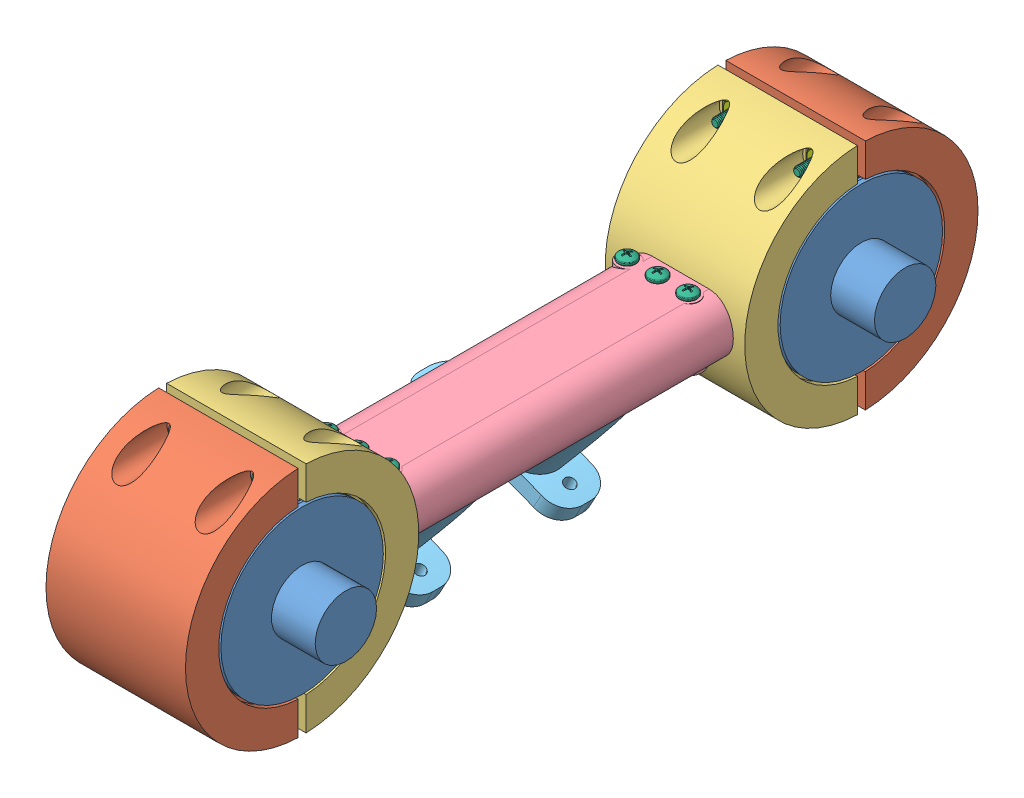
SolidWorks assembly spoilerassm, configuration Default. Lengths in mm.
Overall size (129.47 120.96 369.32).
48 component instances, 8 part files, 38 mates.
Components (placement in the parent):
- Copy of edf^spoilerassm-1: Copy of edf^spoilerassm [Default] at (232.7544 176.9652 -40.9789) size (85.4 108.65 122.15) (virtual)
  - Copy of edf^Copy of edf_spoilerassm-1: Copy of edf^Copy of edf_spoilerassm [Default] at (17.7715 0 -26.4391) size (85.4 90.8 94.1) (virtual)
  - Part2^Copy of edf_spoilerassm-1: Part2^Copy of edf_spoilerassm [Default] at origin size (65 108.65 52.51) (virtual)
  - Copy of Part2^Copy of edf_spoilerassm-2: Copy of Part2^Copy of edf_spoilerassm [Default] at (-3.166 0 -52.8782) x (1 0 0) z (0 0 -1) size (65 108.65 65.94) (virtual)
- Part3^spoilerassm-1: Part3^spoilerassm [Default] at (229.5884 176.9652 -0.616) x (-1 0 0) z (0 0 1) size (52.1 38.79 156.47) (virtual)
- Copy of edf^spoilerassm-2: Copy of edf^spoilerassm [Default] at (232.7544 176.9652 166.7469) x (1 0 0) z (0 0 -1) size (85.4 108.65 122.15) (virtual)
  - Copy of edf^Copy of edf_spoilerassm-1: Copy of edf^Copy of edf_spoilerassm [Default] at (17.7715 0 -26.4391) size (85.4 90.8 94.1) (virtual)
  - Part2^Copy of edf_spoilerassm-1: Part2^Copy of edf_spoilerassm [Default] at origin size (65 108.65 52.51) (virtual)
  - Copy of Part2^Copy of edf_spoilerassm-2: Copy of Part2^Copy of edf_spoilerassm [Default] at (-3.166 0 -52.8782) x (1 0 0) z (0 0 -1) size (65 108.65 65.94) (virtual)
- scooterbase-1: scooterbase [Default] at (218.1937 -0.4538 -1.886) size (199.84 127 129.54) (hidden)
- Part1^spoilerassm-1: Part1^spoilerassm [Default] at (218.1937 -0.4538 127.654) size (101.69 64.87 27.24) (virtual)
- Part1^spoilerassm-2: Part1^spoilerassm [Default] at (218.1937 -0.4538 57.804) size (101.69 64.87 27.24) (virtual)
- 91735A199_316 Stainless Steel Pan Head Phillips Screw-1: 91735A199_316 Stainless Steel Pan Head Phillips Screw [91735A199] at (265.7603 223.5385 -74.346) x (-0.458456 -0.888717 0) z (0 0 -1) size (8.18 8.18 28.44)
- 91735A199_316 Stainless Steel Pan Head Phillips Screw-2: 91735A199_316 Stainless Steel Pan Head Phillips Screw [91735A199] at (304.63 223.5385 -73.6731) x (-0.458456 -0.888717 0) z (0 0 -1) size (8.18 8.18 28.44)
- 91735A199_316 Stainless Steel Pan Head Phillips Screw-3: 91735A199_316 Stainless Steel Pan Head Phillips Screw [91735A199] at (304.63 223.5385 200.114) x (0.763911 -0.645321 0) z (0 0 1) size (8.18 8.18 28.44)
- 91735A199_316 Stainless Steel Pan Head Phillips Screw-4: 91735A199_316 Stainless Steel Pan Head Phillips Screw [91735A199] at (265.7603 223.5385 200.114) x (-0.385326 -0.922781 0) z (0 0 1) size (8.18 8.18 28.44)
- 90480A009_Low-Strength Steel Hex Nut-2: 90480A009_Low-Strength Steel Hex Nut [90480A009] at (304.63 223.5385 184.6705) x (0.999997 0.002605 0) z (-0.002605 0.999997 0) size (8.73 3.79 10.08)
- 90480A009_Low-Strength Steel Hex Nut-3: 90480A009_Low-Strength Steel Hex Nut [90480A009] at (265.7603 223.5385 184.6705) x (0.52328 0.852161 0) z (-0.852161 0.52328 0) size (8.73 3.79 10.08)
- 90480A009_Low-Strength Steel Hex Nut-4: 90480A009_Low-Strength Steel Hex Nut [90480A009] at (265.7603 223.5385 -58.9025) x (0.999763 0.021771 0) z (-0.021771 0.999763 0) size (8.73 3.79 10.08)
- 90480A009_Low-Strength Steel Hex Nut-5: 90480A009_Low-Strength Steel Hex Nut [90480A009] at (304.63 223.5385 -58.9025) x (0.502449 0.864607 0) z (-0.864607 0.502449 0) size (8.73 3.79 10.08)
- 91735A199_316 Stainless Steel Pan Head Phillips Screw-5: 91735A199_316 Stainless Steel Pan Head Phillips Screw [91735A199] at (304.63 130.3205 -73.6731) x (-0.458456 -0.888717 0) z (0 0 -1) size (8.18 8.18 28.44)
- 91735A199_316 Stainless Steel Pan Head Phillips Screw-6: 91735A199_316 Stainless Steel Pan Head Phillips Screw [91735A199] at (304.63 130.3205 200.114) x (0.763911 -0.645321 0) z (0 0 1) size (8.18 8.18 28.44)
- 91735A199_316 Stainless Steel Pan Head Phillips Screw-7: 91735A199_316 Stainless Steel Pan Head Phillips Screw [91735A199] at (265.7603 130.3205 200.114) x (-0.385326 -0.922781 0) z (0 0 1) size (8.18 8.18 28.44)
- 90480A009_Low-Strength Steel Hex Nut-6: 90480A009_Low-Strength Steel Hex Nut [90480A009] at (304.63 130.3205 184.6705) x (0.999997 0.002605 0) z (-0.002605 0.999997 0) size (8.73 3.79 10.08)
- 90480A009_Low-Strength Steel Hex Nut-7: 90480A009_Low-Strength Steel Hex Nut [90480A009] at (265.7603 130.3205 184.6705) x (0.52328 0.852161 0) z (-0.852161 0.52328 0) size (8.73 3.79 10.08)
- 90480A009_Low-Strength Steel Hex Nut-8: 90480A009_Low-Strength Steel Hex Nut [90480A009] at (265.7603 130.3205 -58.9025) x (0.999763 0.021771 0) z (-0.021771 0.999763 0) size (8.73 3.79 10.08)
- 90480A009_Low-Strength Steel Hex Nut-9: 90480A009_Low-Strength Steel Hex Nut [90480A009] at (304.63 130.3205 -58.9025) x (0.502449 0.864607 0) z (-0.864607 0.502449 0) size (8.73 3.79 10.08)
- 91735A199_316 Stainless Steel Pan Head Phillips Screw-8: 91735A199_316 Stainless Steel Pan Head Phillips Screw [91735A199] at (265.7603 130.3205 -74.346) x (-0.458456 -0.888717 0) z (0 0 -1) size (8.18 8.18 28.44)
- 90480A009_Low-Strength Steel Hex Nut-10: 90480A009_Low-Strength Steel Hex Nut [90480A009] at (294.8896 162.5507 -7.3301) x (-0.010668 0 0.999943) z (-0.999943 0 -0.010668) size (8.73 3.79 10.08)
- 91735A199_316 Stainless Steel Pan Head Phillips Screw-9: 91735A199_316 Stainless Steel Pan Head Phillips Screw [91735A199] at (294.8896 189.7922 -7.3301) x (-0.174317 0 0.98469) z (0 1 0) size (8.18 8.18 28.44)
- 90480A009_Low-Strength Steel Hex Nut-11: 90480A009_Low-Strength Steel Hex Nut [90480A009] at (294.8896 162.5507 132.8779) x (-0.010668 0 0.999943) z (-0.999943 0 -0.010668) size (8.73 3.79 10.08)
- 90480A009_Low-Strength Steel Hex Nut-12: 90480A009_Low-Strength Steel Hex Nut [90480A009] at (280.6656 162.5507 -7.3301) x (-0.010668 0 0.999943) z (-0.999943 0 -0.010668) size (8.73 3.79 10.08)
- 90480A009_Low-Strength Steel Hex Nut-13: 90480A009_Low-Strength Steel Hex Nut [90480A009] at (280.6656 162.5507 132.8779) x (-0.010668 0 0.999943) z (-0.999943 0 -0.010668) size (8.73 3.79 10.08)
- 90480A009_Low-Strength Steel Hex Nut-14: 90480A009_Low-Strength Steel Hex Nut [90480A009] at (266.4416 162.5507 -7.3301) x (-0.010668 0 0.999943) z (-0.999943 0 -0.010668) size (8.73 3.79 10.08)
- 90480A009_Low-Strength Steel Hex Nut-15: 90480A009_Low-Strength Steel Hex Nut [90480A009] at (266.4416 162.5507 132.8779) x (-0.010668 0 0.999943) z (-0.999943 0 -0.010668) size (8.73 3.79 10.08)
- 91735A199_316 Stainless Steel Pan Head Phillips Screw-10: 91735A199_316 Stainless Steel Pan Head Phillips Screw [91735A199] at (294.8896 189.7922 132.8779) x (-0.174317 0 0.98469) z (0 1 0) size (8.18 8.18 28.44)
- 91735A199_316 Stainless Steel Pan Head Phillips Screw-11: 91735A199_316 Stainless Steel Pan Head Phillips Screw [91735A199] at (280.6656 189.7922 -7.3301) x (-0.174317 0 0.98469) z (0 1 0) size (8.18 8.18 28.44)
- 91735A199_316 Stainless Steel Pan Head Phillips Screw-12: 91735A199_316 Stainless Steel Pan Head Phillips Screw [91735A199] at (280.6656 189.7922 132.8779) x (-0.174317 0 0.98469) z (0 1 0) size (8.18 8.18 28.44)
- 91735A199_316 Stainless Steel Pan Head Phillips Screw-13: 91735A199_316 Stainless Steel Pan Head Phillips Screw [91735A199] at (266.4416 189.7922 -7.3301) x (-0.174317 0 0.98469) z (0 1 0) size (8.18 8.18 28.44)
- 91735A199_316 Stainless Steel Pan Head Phillips Screw-14: 91735A199_316 Stainless Steel Pan Head Phillips Screw [91735A199] at (266.4416 189.7922 132.8779) x (-0.174317 0 0.98469) z (0 1 0) size (8.18 8.18 28.44)
- 90480A009_Low-Strength Steel Hex Nut-16: 90480A009_Low-Strength Steel Hex Nut [90480A009] at (265.7514 158.1057 84.1565) x (0.869697 0.493586 0) z (-0.493586 0.869697 0) size (8.73 3.79 10.08)
- 91735A199_316 Stainless Steel Pan Head Phillips Screw-15: 91735A199_316 Stainless Steel Pan Head Phillips Screw [91735A199] at (265.7514 158.1057 109.874) x (0.763642 -0.64564 0) z (0 0 1) size (8.18 8.18 28.44)
- 91735A199_316 Stainless Steel Pan Head Phillips Screw-16: 91735A199_316 Stainless Steel Pan Head Phillips Screw [91735A199] at (265.7514 158.1057 40.024) x (0.763642 -0.64564 0) z (0 0 1) size (8.18 8.18 28.44)
- 91735A199_316 Stainless Steel Pan Head Phillips Screw-17: 91735A199_316 Stainless Steel Pan Head Phillips Screw [91735A199] at (282.6678 158.1057 109.874) x (0.763642 -0.64564 0) z (0 0 1) size (8.18 8.18 28.44)
- 91735A199_316 Stainless Steel Pan Head Phillips Screw-18: 91735A199_316 Stainless Steel Pan Head Phillips Screw [91735A199] at (282.6678 158.1057 40.024) x (0.763642 -0.64564 0) z (0 0 1) size (8.18 8.18 28.44)
- 90480A009_Low-Strength Steel Hex Nut-17: 90480A009_Low-Strength Steel Hex Nut [90480A009] at (265.7514 158.1057 14.3065) x (0.869697 0.493586 0) z (-0.493586 0.869697 0) size (8.73 3.79 10.08)
- 90480A009_Low-Strength Steel Hex Nut-18: 90480A009_Low-Strength Steel Hex Nut [90480A009] at (282.6678 158.1057 84.1565) x (0.869697 0.493586 0) z (-0.493586 0.869697 0) size (8.73 3.79 10.08)
- 90480A009_Low-Strength Steel Hex Nut-19: 90480A009_Low-Strength Steel Hex Nut [90480A009] at (282.6678 158.1057 14.3065) x (0.869697 0.493586 0) z (-0.493586 0.869697 0) size (8.73 3.79 10.08)
Mates (geometry in assembly coordinates):
- InPlace1: in place: plane of scooterbase-1 through (218.1937 -0.4538 127.654) normal (0 0 1); plane of ? through (0 0 127.654) normal (0 0 1); moOrthogonalPlaneRef_w of scooterbase-1 through (218.1937 -0.4538 127.654) normal (0 0 1); plane of ? through (0 0 127.654) normal (0 1 0); plane of scooterbase-1 through (218.1937 -0.4538 127.654) normal (0 0 1); plane of ? through (0 0 127.654) normal (1 0 0); plane of scooterbase-1 through (218.1937 -0.4538 127.654) normal (0 0 1); unknown of Part1^spoilerassm-1
- Coincident1: coincident aligned: plane of scooterbase-1; plane of Part1^spoilerassm-1
- Coincident2: coincident aligned: moOrthogonalPlaneRef_w of scooterbase-1 through (218.1937 -0.4538 127.654) normal (0 1 0); plane of Part1^spoilerassm-1 through (218.1937 -0.4538 127.654) normal (0 1 0)
- Coincident3: coincident anti-aligned: moOrthogonalPlaneRef_w of scooterbase-1 through (218.1937 -0.4538 127.654) normal (-1 0 0); plane of Part1^spoilerassm-1 through (218.1937 -0.4538 127.654) normal (1 0 0)
- InPlace2: in place: plane of ? through (212.0241 211.3353 105.2581) normal (0 0 1); plane of ? through (0 0 105.2581) normal (0 0 1); plane of ? through (212.0241 211.3353 105.2581) normal (0 0 1); plane of ? through (0 0 105.2581) normal (0 1 0); plane of ? through (212.0241 211.3353 105.2581) normal (0 0 1); plane of ? through (0 0 105.2581) normal (1 0 0); plane of Copy of edf^spoilerassm-1/Copy of Part2^Copy of edf_spoilerassm-2 through (229.5884 176.9652 -0.616) normal (0 0 1); unknown of Part3^spoilerassm-1
- Coincident4: coincident aligned: plane of Copy of edf^spoilerassm-1/Copy of Part2^Copy of edf_spoilerassm-2; plane of Part3^spoilerassm-1
- Coincident5: coincident aligned: moOrthogonalPlaneRef_w of Copy of edf^spoilerassm-1/Copy of Part2^Copy of edf_spoilerassm-2 through (229.5884 176.9652 -0.616) normal (0 -1 0); plane of Part3^spoilerassm-1 through (229.5884 176.9652 -0.616) normal (0 -1 0)
- Coincident6: coincident anti-aligned: moOrthogonalPlaneRef_w of Copy of edf^spoilerassm-1/Copy of Part2^Copy of edf_spoilerassm-2 through (229.5884 176.9652 -0.616) normal (1 0 0); plane of Part3^spoilerassm-1 through (229.5884 176.9652 -0.616) normal (-1 0 0)
- Concentric3: concentric anti-aligned: cylinder of Part3^spoilerassm-1 through (270.9323 176.9652 126.384) axis (0 0 -1) radius 11.049; cylinder of Copy of edf^spoilerassm-2/Copy of Part2^Copy of edf_spoilerassm-2 through (270.9323 176.9652 126.384) axis (0 0 1) radius 10.287
- Concentric4: concentric aligned: cylinder of Part3^spoilerassm-1 through (250.5258 176.9652 193.186) axis (-1 0 0) radius 54.356; cylinder of Copy of edf^spoilerassm-2/Copy of Part2^Copy of edf_spoilerassm-2 through (250.5258 176.9652 193.186) axis (-1 0 0) radius 54.356
- Concentric5: concentric anti-aligned: cylinder of scooterbase-1 through (218.1937 -0.4538 127.654) axis (0 0 -1) radius 127; cylinder of Part1^spoilerassm-2 through (218.1937 -0.4538 15.894) axis (0 0 1) radius 127
- Concentric6: concentric anti-aligned: cylinder of scooterbase-1 through (218.1937 124.0062 27.959) axis (0 1 0) radius 2.54; cylinder of Part1^spoilerassm-2 through (218.1937 177.3462 27.959) axis (0 -1 0) radius 2.54
- Width1: width anti-aligned: plane of scooterbase-1 through (218.1937 -0.4538 -1.886) normal (0 0 -1); plane of Part3^spoilerassm-1 through (218.1937 -0.4538 127.654) normal (0 0 1); plane of scooterbase-1 through (229.5884 161.5982 139.5173) normal (0 0 1); plane of Part3^spoilerassm-1 through (229.5884 161.5982 -13.7493) normal (0 0 -1)
- Lock1: lock: unknown of Part3^spoilerassm-1; unknown of Part1^spoilerassm-1
- Concentric7: concentric anti-aligned: circle of Copy of edf^spoilerassm-1/Part2^Copy of edf_spoilerassm-1; circle of 91735A199_316 Stainless Steel Pan Head Phillips Screw-1
- Coincident1: coincident anti-aligned: plane of Copy of edf^spoilerassm-1/Part2^Copy of edf_spoilerassm-1 through (265.7603 223.5385 -74.346) normal (0 0 -1); plane of 91735A199_316 Stainless Steel Pan Head Phillips Screw-1 through (263.9093 224.4934 -74.346) normal (0 0 1)
- Concentric8: concentric anti-aligned: circle of Copy of edf^spoilerassm-1/Part2^Copy of edf_spoilerassm-1; circle of 91735A199_316 Stainless Steel Pan Head Phillips Screw-2
- Concentric9: concentric anti-aligned: circle of Copy of edf^spoilerassm-2/Part2^Copy of edf_spoilerassm-1; circle of 91735A199_316 Stainless Steel Pan Head Phillips Screw-3
- Coincident2: coincident anti-aligned: plane of Copy of edf^spoilerassm-2/Part2^Copy of edf_spoilerassm-1 through (304.63 223.5385 200.114) normal (0 0 1); plane of 91735A199_316 Stainless Steel Pan Head Phillips Screw-3 through (305.9741 225.1296 200.114) normal (0 0 -1)
- Concentric10: concentric anti-aligned: circle of Copy of edf^spoilerassm-2/Part2^Copy of edf_spoilerassm-1; circle of 91735A199_316 Stainless Steel Pan Head Phillips Screw-4
- Concentric12: concentric anti-aligned: circle of 91735A199_316 Stainless Steel Pan Head Phillips Screw-3; circle of 90480A009_Low-Strength Steel Hex Nut-2
- Coincident5: coincident anti-aligned: plane of Copy of edf^spoilerassm-2/Copy of Part2^Copy of edf_spoilerassm-2 through (229.5884 176.9652 186.258) normal (0 0 -1); plane of 90480A009_Low-Strength Steel Hex Nut-2 through (300.271 221.0067 186.258) normal (0 0 1)
- Concentric14: concentric anti-aligned: cone of 91735A199_316 Stainless Steel Pan Head Phillips Screw-4; cone of 90480A009_Low-Strength Steel Hex Nut-3 through (265.7603 223.5385 183.083) axis (0 0 -1)
- Coincident6: coincident anti-aligned: plane of Copy of edf^spoilerassm-2/Copy of Part2^Copy of edf_spoilerassm-2 through (229.5884 176.9652 186.258) normal (0 0 -1); plane of 90480A009_Low-Strength Steel Hex Nut-3 through (265.6238 218.4994 186.258) normal (0 0 1)
- Concentric15: concentric aligned: circle of 91735A199_316 Stainless Steel Pan Head Phillips Screw-2; circle of 90480A009_Low-Strength Steel Hex Nut-5
- Parallel1: parallel anti-aligned: plane of Copy of edf^spoilerassm-1/Copy of Part2^Copy of edf_spoilerassm-2 through (229.5884 176.9652 -60.49) normal (0 0 1); plane of 90480A009_Low-Strength Steel Hex Nut-5 through (304.6157 218.4976 -60.49) normal (0 0 -1)
- Coincident7: coincident anti-aligned: plane of Copy of edf^spoilerassm-1/Copy of Part2^Copy of edf_spoilerassm-2 through (229.5884 176.9652 -60.49) normal (0 0 1); plane of 90480A009_Low-Strength Steel Hex Nut-5 through (304.6157 218.4976 -60.49) normal (0 0 -1)
- Coincident8: coincident anti-aligned: plane of Copy of edf^spoilerassm-1/Copy of Part2^Copy of edf_spoilerassm-2 through (229.5884 176.9652 -60.49) normal (0 0 1); plane of 90480A009_Low-Strength Steel Hex Nut-4 through (261.4506 220.9236 -60.49) normal (0 0 -1)
- Concentric16: concentric anti-aligned: circle of 91735A199_316 Stainless Steel Pan Head Phillips Screw-1; circle of 90480A009_Low-Strength Steel Hex Nut-4
- Concentric17: concentric aligned: circle of Part3^spoilerassm-1; circle of 91735A199_316 Stainless Steel Pan Head Phillips Screw-9
- Coincident9: coincident anti-aligned: plane of Part3^spoilerassm-1 through (229.5884 189.7922 126.384) normal (0 1 0); plane of 91735A199_316 Stainless Steel Pan Head Phillips Screw-9 through (296.9405 189.7922 -6.9671) normal (0 -1 0)
- Concentric18: concentric anti-aligned: circle of Part3^spoilerassm-1; circle of 90480A009_Low-Strength Steel Hex Nut-10
- Coincident10: coincident anti-aligned: plane of Part3^spoilerassm-1 through (229.5884 164.1382 126.384) normal (0 -1 0); plane of 90480A009_Low-Strength Steel Hex Nut-10 through (297.4565 164.1382 -11.6686) normal (0 1 0)
- Concentric19: concentric anti-aligned: cone of 90480A009_Low-Strength Steel Hex Nut-16 through (265.7514 158.1057 82.569) axis (0 0 -1); circle of 91735A199_316 Stainless Steel Pan Head Phillips Screw-15
- Coincident11: coincident anti-aligned: plane of Copy of edf^spoilerassm-2/Part2^Copy of edf_spoilerassm-1 through (265.7603 223.5385 200.114) normal (0 0 1); plane of 91735A199_316 Stainless Steel Pan Head Phillips Screw-4 through (267.6823 222.736 200.114) normal (0 0 -1)
- Concentric20: concentric anti-aligned: circle of Part1^spoilerassm-1; circle of 91735A199_316 Stainless Steel Pan Head Phillips Screw-15
- Tangent1: tangent: plane of assembly; face of Part1^spoilerassm-1; plane of 90480A009_Low-Strength Steel Hex Nut-16 through (263.1987 153.7588 85.744) normal (0 0 1)
- Tangent2: tangent: plane of assembly; face of Part1^spoilerassm-1; plane of 91735A199_316 Stainless Steel Pan Head Phillips Screw-15 through (267.0961 159.6962 109.874) normal (0 0 -1)
